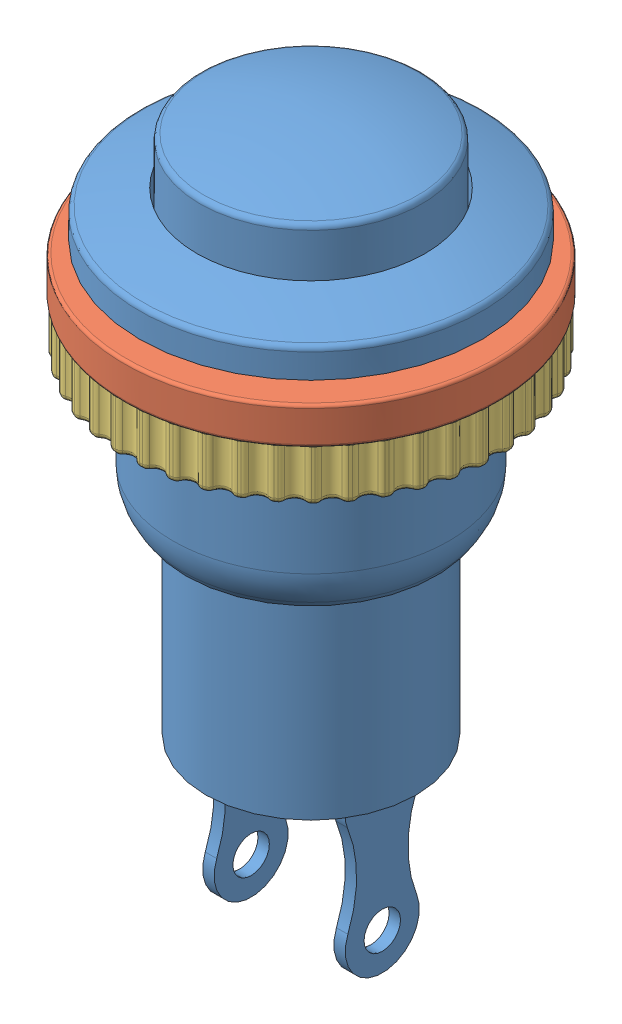
SolidWorks assembly Assemblage1, configuration Défaut. Lengths in mm.
Overall size (18.19 24.8 18.19).
3 component instances, 3 part files, 3 mates.
Components (placement in the parent):
- Push_main-1: Push_main [Défaut] at (-2.0328 -5.3276 24.8) size (12.02 24.8 12.02)
- Push_ring-1: Push_ring [Défaut] at (-2.0328 6.3256 24.8) x (0.960172 0 0.279408) z (-0.279408 0 0.960172) size (13.1 1.3 13.1)
- Push_screw-1: Push_screw [Défaut] at (-2.0328 7.9974 24.8) x (-0.802228 0 -0.597018) z (-0.597018 0 0.802228) size (13 1.8 13)
Mates (geometry in assembly coordinates):
- Coaxiale1: concentric anti-aligned: cylinder of Push_main-1 through (-2.0328 -5.3276 24.8) axis (0 -1 0) radius 4.84; circle of Push_ring-1
- Coïncidente1: coincident anti-aligned: plane of Push_ring-1 through (3.0273 7.9974 26.2725) normal (0 -1 0); plane of Push_screw-1 through (-2.0328 7.9974 24.8) normal (0 1 0)
- Coaxiale2: concentric anti-aligned: cylinder of Push_main-1 through (-2.0328 -5.3276 24.8) axis (0 -1 0) radius 4.84; cylinder of Push_screw-1 through (-2.0328 6.1974 24.8) axis (0 1 0) radius 4.9
